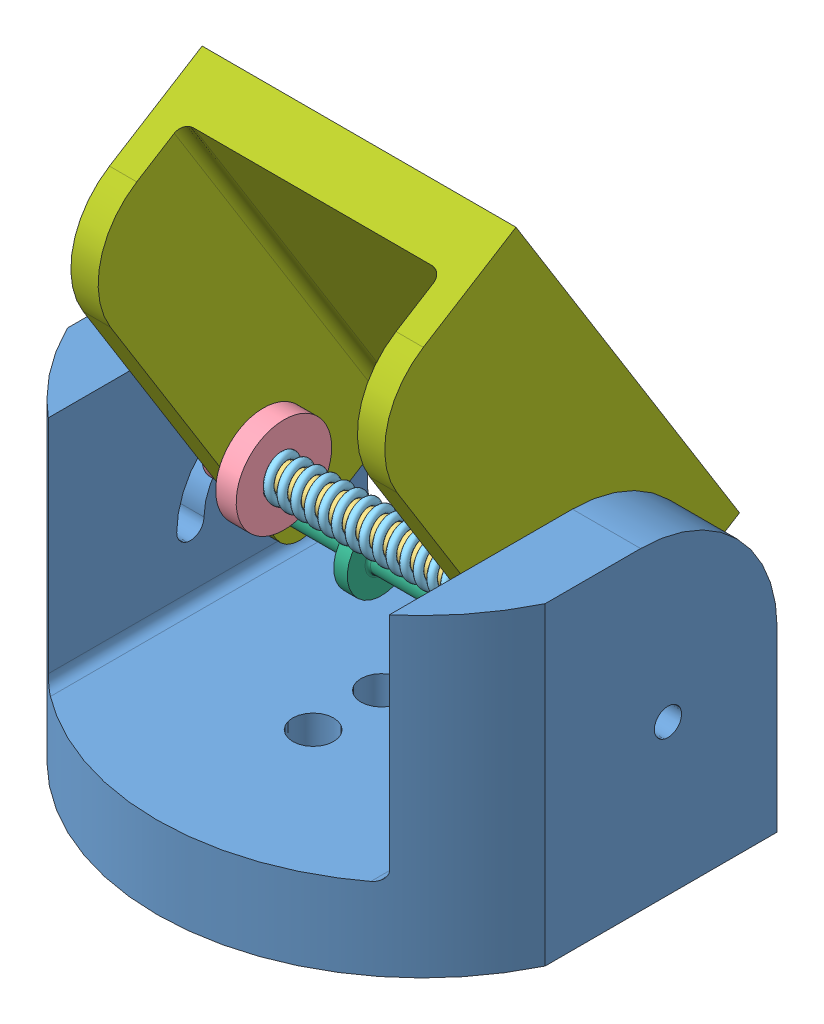
SolidWorks assembly Hinge ASM, configuration Default. Lengths in mm.
Overall size (39 41.96 31.2).
8 component instances, 7 part files, 6 mates.
Components (placement in the parent):
- Base-1: Base [Default] at (11.1933 16.6188 42.1623) size (35 23 27.96)
- Plunger-1: Plunger [Default] at (3.8079 37.9715 21.6272) x (0 0.821196 0.570646) z (0 -0.570646 0.821196) size (8 38.09 8)
  - Plunger Button-1: Plunger Button [Default] at (-0.0641 3.1147 10.6111) size (8 11 8)
  - Plunger Spring Shaft-1: Plunger Spring Shaft [Default] at (-0.0641 2.6147 10.6111) x (1 0 0) z (0 -1 0) size (2 2 25)
  - Plunger Spring-Button Mate-1: Plunger Spring-Button Mate [Default] at (-0.0641 0.6147 10.6111) size (7 4.5 7)
  - 9657K294_Compression Spring-1: 9657K294_Compression Spring [9657K294] at (0.2039 1.1759 10.8003) x (0.000076 0.008726 -0.999962) z (0.008726 0.999924 0.008727) size (3.64 3.64 25.4)
- Axis Shaft-1: Axis Shaft [Default] at (23.6933 27.6188 27.6623) x (0 -0.689407 -0.724374) z (0 0.724374 -0.689407) size (5 25 5)
- Swing Piece-1: Swing Piece [Default] at (11.1933 45.4211 24.6082) x (1 0 0) z (0 -0.52842 0.848983) size (23 31 14)
Mates (geometry in assembly coordinates):
- Coincident1: coincident anti-aligned: plane of Base-1 through (-1.3067 16.6188 42.1623) normal (1 0 0); plane of Plunger-1/Plunger Spring-Button Mate-1 through (-1.3067 31.8637 30.3044) normal (-1 0 0)
- Concentric2: concentric anti-aligned: cylinder of Base-1 through (-16.2062 27.6188 27.6623) axis (1 0 0) radius 1; cylinder of Axis Shaft-1 through (-1.3067 27.6188 27.6623) axis (-1 0 0) radius 1
- Coincident2: coincident anti-aligned: plane of Base-1 through (-1.3067 16.6188 42.1623) normal (1 0 0); plane of Axis Shaft-1 through (-1.3067 26.9294 26.9379) normal (-1 0 0)
- Coincident3: coincident anti-aligned: plane of Plunger-1/Plunger Spring-Button Mate-1 through (1.6933 34.7379 32.3016) normal (-1 0 0); plane of Swing Piece-1 through (1.6933 45.4211 24.6082) normal (1 0 0)
- Concentric3: concentric anti-aligned: cylinder of Axis Shaft-1 through (-1.3067 27.6188 27.6623) axis (-1 0 0) radius 1; cylinder of Swing Piece-1 through (-0.3067 27.6188 27.6623) axis (1 0 0) radius 1
- Concentric4: concentric anti-aligned: cylinder of Plunger-1/Plunger Spring Shaft-1 through (26.1933 31.8637 30.3044) axis (-1 0 0) radius 1; cylinder of Swing Piece-1 through (-0.3067 31.8637 30.3044) axis (1 0 0) radius 1
